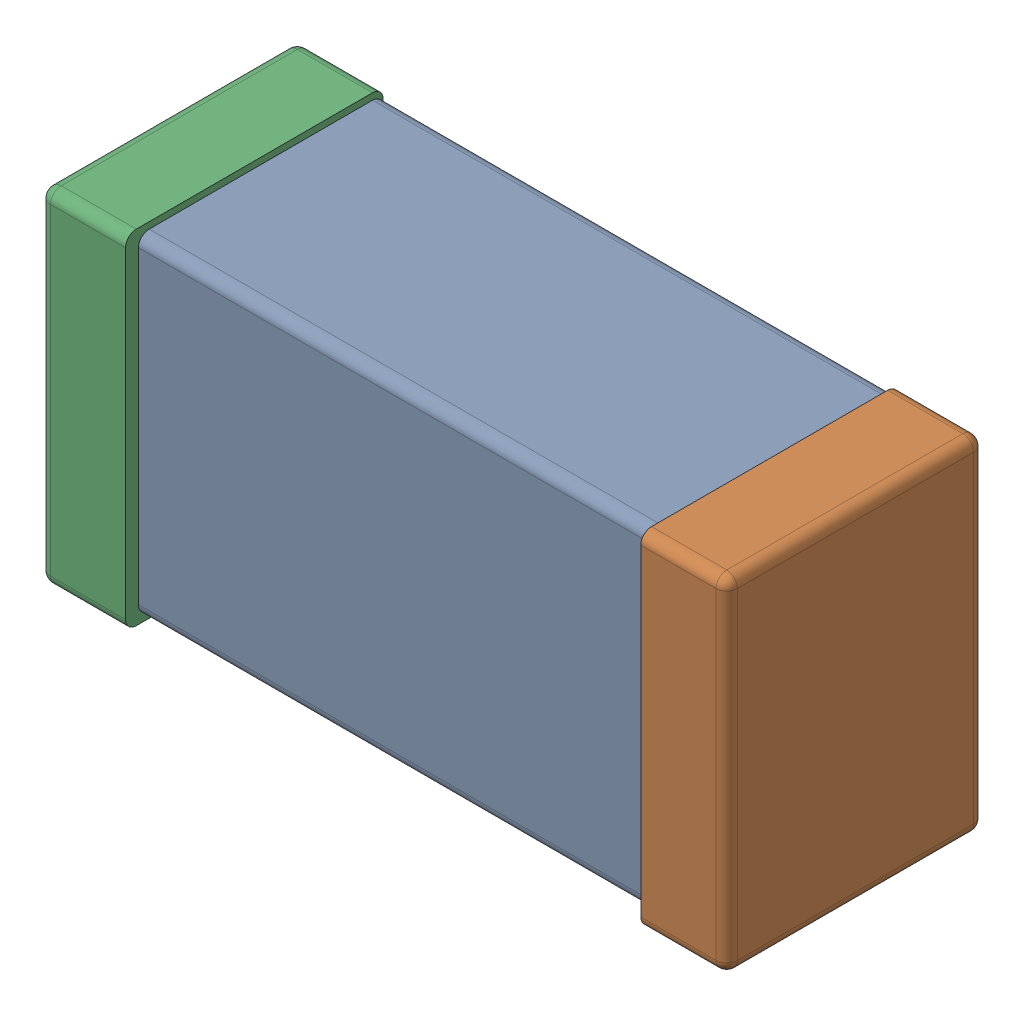
SolidWorks assembly C0603_060_3, configuration Standard. Lengths in mm.
Overall size (1.6 0.8 0.6).
3 component instances, 3 part files, 0 mates.
Components (placement in the parent):
- Part 3_1-1: Part 3_1 [Standard] at (0 0 -23.815) size (1.4 0.77 0.57)
- Part 2_1-1: Part 2_1 [Standard] at (0 0 -23.8) size (0.2 0.8 0.6)
- Part 1_1-1: Part 1_1 [Standard] at (0 0 -23.8) size (0.2 0.8 0.6)
